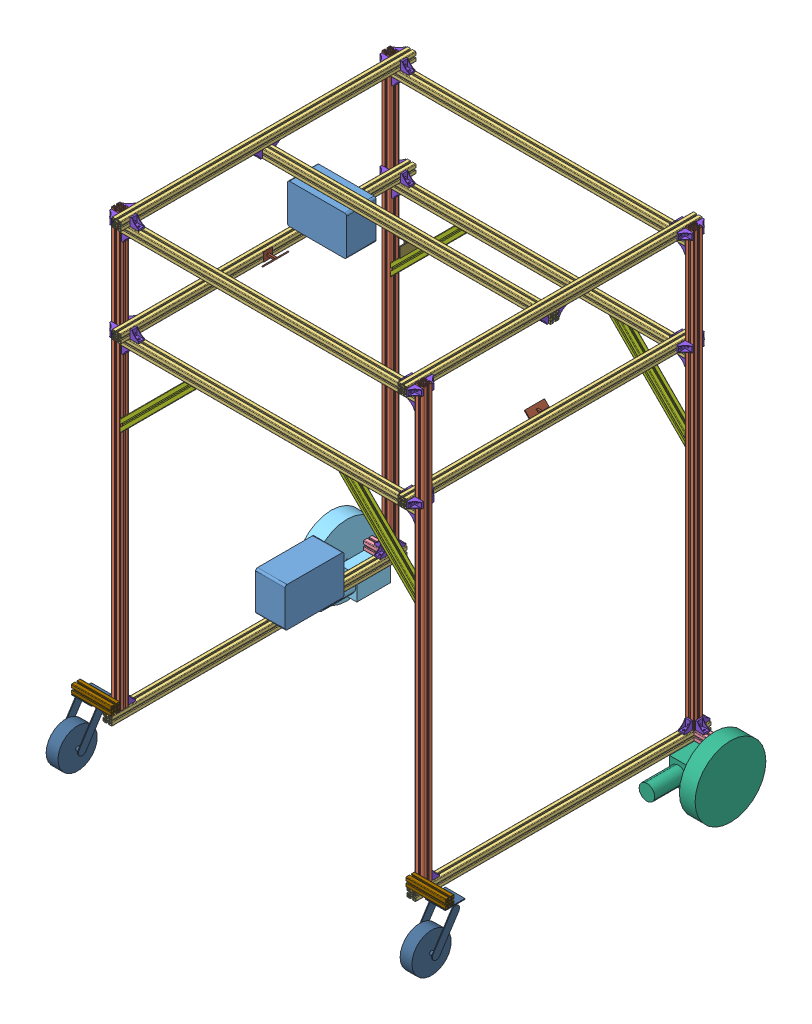
SolidWorks assembly cad, configuration Default. Lengths in mm.
Overall size (2030 2475 1715).
77 component instances, 13 part files, 154 mates.
Components (placement in the parent):
- frame-1: part_frame [Default] at origin size (1890 2245 1520) (hidden)
- box-1: part_box [Default] at (-233.0218 271.2252 -505.6193) x (0 0 -1) z (1 0 0) size (300 200 150)
- box-2: part_box [Default] at (46.9782 2181.2252 -538.1193) size (300 200 150)
- NFSL8_4545_2200-1: part_NFSL8_4545_2200 [Default] at (1374.4782 271.2252 -1128.1193) x (1 0 0) z (0 -1 0) size (45 45 2200)
- NFSL8_4545_2200-3: part_NFSL8_4545_2200 [Default] at (-170.5218 271.2252 -1128.1193) x (1 0 0) z (0 -1 0) size (45 45 2200)
- NFSL8_4545_2200-4: part_NFSL8_4545_2200 [Default] at (1374.4782 271.2252 246.8807) x (1 0 0) z (0 -1 0) size (45 45 2200)
- NFSL8_4545_2200-5: part_NFSL8_4545_2200 [Default] at (-170.5218 271.2252 246.8807) x (1 0 0) z (0 -1 0) size (45 45 2200)
- NFSL8_4545_1500-1: part_NFSL8_4545_1500 [Default] at (1374.4782 248.7252 -1190.6193) x (1 0 0) z (0 0 -1) size (45 45 1500)
- NFSL8_4545_1500-2: part_NFSL8_4545_1500 [Default] at (-170.5218 248.7252 -1190.6193) x (1 0 0) z (0 0 -1) size (45 45 1500)
- NFSL8_4545_90-1: part_NFSL8_4545_90 [Default] at (-193.0218 248.7252 -1128.1193) x (0 0 -1) z (1 0 0) size (45 45 90)
- NFSL8_4545_90-2: part_NFSL8_4545_90 [Default] at (1486.9782 248.7252 -1128.1193) x (0 0 -1) z (1 0 0) size (45 45 90)
- NFSL8_4545_1500-3: part_NFSL8_4545_1500 [Default] at (-125.5218 2448.7252 309.3807) size (45 45 1500)
- NFSL8_4545_1500-4: part_NFSL8_4545_1500 [Default] at (1329.4782 2448.7252 309.3807) size (45 45 1500)
- NFSL8_4545_1500-5: part_NFSL8_4545_1500 [Default] at (1351.9782 2403.7252 -1128.1193) x (0 0 -1) z (1 0 0) size (45 45 1500)
- NFSL8_4545_1500-8: part_NFSL8_4545_1500 [Default] at (1351.9782 2403.7252 -440.6193) x (0 0 -1) z (1 0 0) size (45 45 1500)
- NFSL8_4545_1500-9: part_NFSL8_4545_1500 [Default] at (1351.9782 2403.7252 246.8807) x (0 0 -1) z (1 0 0) size (45 45 1500)
- NFSL8_4545_1500-10: part_NFSL8_4545_1500 [Default] at (-125.5218 1953.7252 309.3807) size (45 45 1500)
- NFSL8_4545_1500-11: part_NFSL8_4545_1500 [Default] at (1329.4782 1953.7252 309.3807) size (45 45 1500)
- NFSL8_4545_1500-12: part_NFSL8_4545_1500 [Default] at (1351.9782 1908.7252 246.8807) x (0 0 -1) z (1 0 0) size (45 45 1500)
- NFSL8_4545_1500-13: part_NFSL8_4545_1500 [Default] at (1351.9782 1908.7252 -1128.1193) x (0 0 -1) z (1 0 0) size (45 45 1500)
- frontL-1: part_frontL [Default] at (-193.0218 106.2252 -1150.6193) x (-1 0 0) z (0 0 -1) size (220 360 430)
- frontR-1: part_frontR [Default] at (1396.9782 106.2252 -1150.6193) x (-1 0 0) z (0 0 -1) size (220 360 430)
- HFSL8_4545_550_LCT45_RCT45-1: part_HFSL8_4545_550_LCT45_RCT45 [Default] at (224.977 1902.1351 -1128.1193) x (0 0 -1) z (0.707107 0.707107 0) size (45 45 550)
- HFSL8_4545_550_LCT45_RCT45-2: part_HFSL8_4545_550_LCT45_RCT45 [Default] at (978.9794 1902.1351 -1128.1193) x (0 0 1) z (-0.707107 0.707107 0) size (45 45 550)
- HFSL8_4545_550_LCT45_RCT45-3: part_HFSL8_4545_550_LCT45_RCT45 [Default] at (224.977 1902.1351 246.8807) x (0 0 -1) z (0.707107 0.707107 0) size (45 45 550)
- HFSL8_4545_550_LCT45_RCT45-4: part_HFSL8_4545_550_LCT45_RCT45 [Default] at (978.9794 1902.1351 246.8807) x (0 0 1) z (-0.707107 0.707107 0) size (45 45 550)
- HBLFSN8-1: part_HBLFSN8 [Default] at (-170.5218 271.2252 -1105.6193) size (30 45 45)
- HBLFSN8-2: part_HBLFSN8 [Default] at (-193.0218 271.2252 -1128.1193) x (0 0 1) z (-1 0 0) size (30 45 45)
- HBLFSN8-3: part_HBLFSN8 [Default] at (-170.5218 268.8279 -1150.6193) x (-1 0 0) z (0 0 -1) size (30 45 45)
- HBLFSN8-4: part_HBLFSN8 [Default] at (1396.9782 271.2252 -1128.1193) x (0 0 -1) z (1 0 0) size (30 45 45)
- HBLFSN8-5: part_HBLFSN8 [Default] at (1374.4782 271.2252 -1150.6193) x (-1 0 0) z (0 0 -1) size (30 45 45)
- HBLFSN8-6: part_HBLFSN8 [Default] at (1374.4782 271.2252 -1105.6193) size (30 45 45)
- HBLFSN8-7: part_HBLFSN8 [Default] at (-103.0218 1931.2252 246.8807) x (0 0 -1) z (1 0 0) size (30 45 45)
- HBLFSN8-8: part_HBLFSN8 [Default] at (-148.0218 1886.2252 246.8807) x (0 0 1) z (1 0 0) size (30 45 45)
- HBLFSN8-9: part_HBLFSN8 [Default] at (-148.0218 1953.7252 224.3807) x (0 1 0) z (-1 0 0) size (30 45 45)
- HBLFSN8-10: part_HBLFSN8 [Default] at (1306.9782 1931.2252 246.8807) x (0 0 1) z (-1 0 0) size (30 45 45)
- HBLFSN8-11: part_HBLFSN8 [Default] at (1351.9782 1886.2252 246.8807) x (0 0 -1) z (-1 0 0) size (30 45 45)
- HBLFSN8-12: part_HBLFSN8 [Default] at (1351.9782 1953.7252 224.3807) x (0 1 0) z (0 0 -1) size (30 45 45)
- HBLFSN8-13: part_HBLFSN8 [Default] at (1329.4782 2426.2252 -418.1193) x (-1 0 0) z (0 0 1) size (30 45 45)
- HBLFSN8-14: part_HBLFSN8 [Default] at (1329.4782 2426.2252 -463.1193) x (1 0 0) z (0 0 -1) size (30 45 45)
- HBLFSN8-15: part_HBLFSN8 [Default] at (-125.5218 2426.2252 -463.1193) x (1 0 0) z (0 0 -1) size (30 45 45)
- HBLFSN8-16: part_HBLFSN8 [Default] at (-125.5218 2426.2252 -418.1193) x (-1 0 0) z (0 0 1) size (30 45 45)
- HBLFSN8-18: part_HBLFSN8 [Default] at (-170.5218 271.2252 224.3807) x (-1 0 0) z (0 0 -1) size (30 45 45)
- HBLFSN8-19: part_HBLFSN8 [Default] at (1374.4782 271.2252 224.3807) x (-1 0 0) z (0 0 -1) size (30 45 45)
- HBLFSN8-22: part_HBLFSN8 [Default] at (1306.9782 1931.2252 -1128.1193) x (0 0 1) z (-1 0 0) size (30 45 45)
- HBLFSN8-23: part_HBLFSN8 [Default] at (1351.9782 1886.2252 -1128.1193) x (0 0 -1) z (-1 0 0) size (30 45 45)
- HBLFSN8-24: part_HBLFSN8 [Default] at (1351.9782 1953.7252 -1105.6193) x (0 -1 0) z (0 0 1) size (30 45 45)
- HBLFSN8-25: part_HBLFSN8 [Default] at (-103.0218 1931.2252 -1128.1193) x (0 0 -1) z (1 0 0) size (30 45 45)
- HBLFSN8-26: part_HBLFSN8 [Default] at (-148.0218 1886.2252 -1128.1193) x (0 0 1) z (1 0 0) size (30 45 45)
- HBLFSN8-27: part_HBLFSN8 [Default] at (-148.0218 1953.7252 -1105.6193) x (0 1 0) z (0 0 1) size (30 45 45)
- HBLFSN8-28: part_HBLFSN8 [Default] at (1351.9782 1953.7252 269.3807) x (0 -1 0) z (0 0 1) size (30 45 45)
- HBLFSN8-29: part_HBLFSN8 [Default] at (1351.9782 1953.7252 -1150.6193) x (0 1 0) z (0 0 -1) size (30 45 45)
- HBLFSN8-30: part_HBLFSN8 [Default] at (-148.0218 1953.7252 -1150.6193) x (0 1 0) z (-1 0 0) size (30 45 45)
- HBLFSN8-31: part_HBLFSN8 [Default] at (-148.0218 1953.7252 269.3807) x (0 1 0) z (0 0 1) size (30 45 45)
- HBLFSN8-32: part_HBLFSN8 [Default] at (-103.0218 2426.2252 -1128.1193) x (0 0 -1) z (1 0 0) size (30 45 45)
- HBLFSN8-33: part_HBLFSN8 [Default] at (1351.9782 2381.2252 246.8807) x (0 0 -1) z (-1 0 0) size (30 45 45)
- HBLFSN8-34: part_HBLFSN8 [Default] at (1306.9782 2426.2252 246.8807) x (0 0 1) z (-1 0 0) size (30 45 45)
- HBLFSN8-35: part_HBLFSN8 [Default] at (1351.9782 2448.7252 269.3807) x (0 -1 0) z (0 0 1) size (30 45 45)
- HBLFSN8-36: part_HBLFSN8 [Default] at (1351.9782 2448.7252 224.3807) x (0 1 0) z (0 0 -1) size (30 45 45)
- HBLFSN8-37: part_HBLFSN8 [Default] at (1351.9782 2448.7252 -1105.6193) x (0 -1 0) z (0 0 1) size (30 45 45)
- HBLFSN8-38: part_HBLFSN8 [Default] at (1351.9782 2448.7252 -1150.6193) x (0 1 0) z (0 0 -1) size (30 45 45)
- HBLFSN8-39: part_HBLFSN8 [Default] at (1306.9782 2426.2252 -1128.1193) x (0 0 1) z (-1 0 0) size (30 45 45)
- HBLFSN8-40: part_HBLFSN8 [Default] at (1351.9782 2381.2252 -1128.1193) x (0 0 -1) z (-1 0 0) size (30 45 45)
- HBLFSN8-41: part_HBLFSN8 [Default] at (-148.0218 2448.7252 269.3807) x (0 1 0) z (0 0 1) size (30 45 45)
- HBLFSN8-42: part_HBLFSN8 [Default] at (-148.0218 2448.7252 224.3807) x (0 1 0) z (-1 0 0) size (30 45 45)
- HBLFSN8-43: part_HBLFSN8 [Default] at (-148.0218 2381.2252 246.8807) x (0 0 1) z (1 0 0) size (30 45 45)
- HBLFSN8-44: part_HBLFSN8 [Default] at (-103.0218 2426.2252 246.8807) x (0 0 -1) z (1 0 0) size (30 45 45)
- HBLFSN8-45: part_HBLFSN8 [Default] at (-148.0218 2381.2252 -1128.1193) x (0 0 1) z (1 0 0) size (30 45 45)
- HBLFSN8-46: part_HBLFSN8 [Default] at (-148.0218 2448.7252 -1105.6193) x (0 1 0) z (0 0 1) size (30 45 45)
- HBLFSN8-47: part_HBLFSN8 [Default] at (-148.0218 2448.7252 -1150.6193) x (0 1 0) z (-1 0 0) size (30 45 45)
- NFSL8_4545_200-3: part_NFSL8_4545_200 [Default] at (-348.0218 293.7252 291.8807) x (0 0 1) z (-1 0 0) size (45 45 200)
- NFSL8_4545_200-4: part_NFSL8_4545_200 [Default] at (1351.9782 293.7252 291.8807) x (0 0 1) z (-1 0 0) size (45 45 200)
- rearwheel-5: part_rearwheel [Default] at (1501.9782 97.2252 364.3807) size (108 274 250)
- rearwheel-6: part_rearwheel [Default] at (-298.0218 97.2252 364.3807) size (108 274 250)
- camerabracket_side-1: part_camerabracket_side [Default] at (-103.0218 1976.2252 -416.1503) x (0 -1 0) z (0 0 1) size (45 57.2 100)
- camerabracket_side-2: part_camerabracket_side [Default] at (1306.9782 1976.2252 -461.1503) x (0 -1 0) z (0 0 -1) size (45 57.2 100)
- camerabracket_top-1: part_camerabracket_top [Default] at (574.846 2381.2252 -463.1193) x (1 0 0) z (0 0 -1) size (45 61.03 100)
Mates (geometry in assembly coordinates):
- Coincident9: coincident aligned: plane of NFSL8_4545_2200-1 through (1396.9782 2471.2252 -1123.1193) normal (1 0 0); plane of NFSL8_4545_1500-1 through (1396.9782 268.2252 309.3807) normal (1 0 0)
- Coincident10: coincident anti-aligned: plane of NFSL8_4545_2200-4 through (1354.9782 271.2252 227.3807) normal (0 -1 0); plane of NFSL8_4545_1500-1 through (1379.4782 271.2252 309.3807) normal (0 1 0)
- Coincident29: coincident aligned: line of NFSL8_4545_2200-3 through (-193.0218 271.2252 -1133.1193) axis (0 0 -1); line of NFSL8_4545_200-1 through (-193.0218 271.2252 241.8807) axis (0 0 -1)
- Perpendicular17: perpendicular: plane of NFSL8_4545_2200-3 through (-193.0218 2471.2252 -1133.1193) normal (-1 0 0); plane of NFSL8_4545_200-1 through (-193.0218 271.2252 241.8807) normal (0 1 0)
- Coincident27: coincident aligned: plane of NFSL8_4545_2200-5 through (-151.0218 2471.2252 269.3807) normal (0 0 1); plane of NFSL8_4545_200-1 through (-193.0218 253.7252 269.3807) normal (0 0 1)
- Coincident30: coincident anti-aligned: line of NFSL8_4545_2200-5 through (-193.0218 271.2252 241.8807) axis (0 0 -1); line of NFSL8_4545_90-1 through (-193.0218 271.2252 -1147.6193) axis (0 0 1)
- Coincident33: coincident aligned: plane of NFSL8_4545_90-1 through (-283.0218 253.7252 -1150.6193) normal (0 0 -1); plane of NFSL8_4545_2200-3 through (-190.0218 2471.2252 -1150.6193) normal (0 0 -1)
- Coincident35: coincident anti-aligned: plane of NFSL8_4545_2200-5 through (-148.0218 2471.2252 251.8807) normal (1 0 0); plane of NFSL8_4545_1500-3 through (-148.0218 2468.2252 -1190.6193) normal (-1 0 0)
- Coincident37: coincident aligned: plane of NFSL8_4545_1500-2 through (-190.0218 268.2252 309.3807) normal (0 0 1); plane of NFSL8_4545_1500-3 through (-145.0218 2429.2252 309.3807) normal (0 0 1)
- Coincident40: coincident anti-aligned: plane of NFSL8_4545_2200-3 through (-148.0218 2471.2252 -1123.1193) normal (1 0 0); plane of NFSL8_4545_1500-5 through (-148.0218 2384.2252 -1108.6193) normal (-1 0 0)
- Coincident43: coincident aligned: plane of NFSL8_4545_2200-3 through (-190.0218 2471.2252 -1147.6193) normal (0 1 0); plane of NFSL8_4545_1500-3 through (-130.5218 2471.2252 -1190.6193) normal (0 1 0)
- Coincident49: coincident anti-aligned: plane of NFSL8_4545_1500-3 through (-120.5218 2426.2252 -1190.6193) normal (0 -1 0); plane of NFSL8_4545_1500-5 through (-148.0218 2426.2252 -1123.1193) normal (0 1 0)
- Coincident55: coincident aligned: plane of NFSL8_4545_2200-3 through (-151.0218 2471.2252 -1105.6193) normal (0 0 1); plane of NFSL8_4545_1500-5 through (-148.0218 2423.2252 -1105.6193) normal (0 0 1)
- Coincident58: coincident: plane of NFSL8_4545_2200-5 through (-148.0218 2471.2252 227.3807) normal (1 0 0); line of NFSL8_4545_1500-12 through (-148.0218 1886.2252 241.8807) axis (0 0 -1)
- Coincident59: coincident anti-aligned: plane of NFSL8_4545_1500-12 through (-148.0218 1931.2252 251.8807) normal (0 1 0); plane of NFSL8_4545_1500-10 through (-120.5218 1931.2252 -1190.6193) normal (0 -1 0)
- Coincident60: coincident aligned: plane of NFSL8_4545_2200-5 through (-165.5218 2471.2252 224.3807) normal (0 0 -1); plane of NFSL8_4545_1500-12 through (-148.0218 1913.7252 224.3807) normal (0 0 -1)
- Distance1: distance = 40 mm: plane of NFSL8_4545_2200-4 through (1369.4782 2471.2252 269.3807) normal (0 0 1); line of NFSL8_4545_1500-1 through (1354.9782 271.2252 309.3807) axis (1 0 0)
- Parallel15: parallel aligned: plane of box-1 through (-233.0218 271.2252 -505.6193) normal (-1 0 0); plane of NFSL8_4545_1500-2 through (-193.0218 253.7252 309.3807) normal (-1 0 0)
- Coincident63: coincident anti-aligned: plane of box-1 through (-83.0218 271.2252 -505.6193) normal (0 -1 0); plane of NFSL8_4545_1500-2 through (-190.0218 271.2252 309.3807) normal (0 1 0)
- Distance2: distance = 300 mm anti-aligned: plane of NFSL8_4545_2200-3 through (-175.5218 2471.2252 -1105.6193) normal (0 0 1); plane of box-1 through (-83.0218 271.2252 -805.6193) normal (0 0 -1)
- Distance3: distance = 40 mm: plane of NFSL8_4545_1500-2 through (-193.0218 253.7252 309.3807) normal (-1 0 0); line of box-1 through (-233.0218 271.2252 -515.6193) axis (0 0 -1)
- Coincident66: coincident anti-aligned: plane of box-2 through (46.9782 2381.2252 -388.1193) normal (0 1 0); plane of NFSL8_4545_1500-8 through (-148.0218 2381.2252 -421.1193) normal (0 -1 0)
- Parallel16: parallel aligned: plane of box-2 through (346.9782 2181.2252 -388.1193) normal (1 0 0); plane of NFSL8_4545_1500-3 through (-103.0218 2453.7252 -1190.6193) normal (1 0 0)
- Distance4: distance = 150 mm anti-aligned: plane of NFSL8_4545_1500-3 through (-103.0218 2429.2252 -1190.6193) normal (1 0 0); plane of box-2 through (46.9782 2181.2252 -388.1193) normal (-1 0 0)
- Distance5: distance = 30 mm aligned: plane of NFSL8_4545_1500-8 through (-148.0218 2398.7252 -418.1193) normal (0 0 1); plane of box-2 through (46.9782 2181.2252 -388.1193) normal (0 0 1)
- Coincident70: coincident anti-aligned: plane of NFSL8_4545_1500-2 through (-193.0218 229.2252 309.3807) normal (-1 0 0); plane of frontL-1 through (-193.0218 106.2252 -1150.6193) normal (1 0 0)
- Coincident71: coincident aligned: plane of NFSL8_4545_90-1 through (-283.0218 229.2252 -1150.6193) normal (0 0 -1); plane of frontL-1 through (-283.0218 106.2252 -1150.6193) normal (0 0 -1)
- Coincident72: coincident aligned: plane of NFSL8_4545_90-2 through (1396.9782 229.2252 -1150.6193) normal (0 0 -1); plane of frontR-1 through (1486.9782 106.2252 -1150.6193) normal (0 0 -1)
- Coincident73: coincident: plane of NFSL8_4545_1500-1 through (1369.4782 226.2252 309.3807) normal (0 -1 0); line of frontR-1 through (1396.9782 226.2252 -980.6193) axis (0 0 -1)
- Coincident74: coincident anti-aligned: plane of NFSL8_4545_1500-1 through (1396.9782 243.7252 309.3807) normal (1 0 0); plane of frontR-1 through (1396.9782 106.2252 -1150.6193) normal (-1 0 0)
- Coincident75: coincident aligned: plane of NFSL8_4545_200-1 through (-393.0218 268.2252 266.3807) normal (-1 0 0); plane of plate-1 through (-393.0218 226.2252 258.3807) normal (-1 0 0)
- Coincident76: coincident aligned: plane of NFSL8_4545_200-1 through (-193.0218 236.0403 258.3807) normal (0 0 1); plane of plate-1 through (-393.0218 226.2252 258.3807) normal (0 0 1)
- Coincident80: coincident anti-aligned: plane of NFSL8_4545_200-1 through (-193.0218 226.2252 251.8807) normal (0 -1 0); plane of plate-1 through (-393.0218 226.2252 258.3807) normal (0 1 0)
- Coincident81: coincident anti-aligned: plane of plate-2 through (1596.9782 226.2252 258.3807) normal (1 0 0); plane of rearwheel-1 through (1596.9782 92.9526 256.107) normal (-1 0 0)
- Tangent1: tangent aligned: plane of plate-2 through (1496.9782 226.2252 258.3807) normal (0 1 0); cylinder of rearwheel-1 through (1600.9782 205.7157 215.0646) axis (-1 0 0) radius 20.5095
- Angle2: planar angle = 1.919862 rad aligned: line of rearwheel-1 through (1600.9782 198.701 195.792) axis (0 -0.939693 0.34202); line of plate-2 through (1596.9782 222.2252 258.3807) axis (0 0 -1)
- Coincident86: coincident anti-aligned: plane of NFSL8_4545_2200-5 through (-148.0218 2471.2252 251.8807) normal (1 0 0); plane of NFSL8_4545_450_LCT45_RCT45-1 through (-148.0218 1658.0271 269.3807) normal (-1 0 0)
- Coincident87: coincident anti-aligned: plane of NFSL8_4545_1500-12 through (-148.0218 1886.2252 266.3807) normal (0 -1 0); plane of NFSL8_4545_450_LCT45_RCT45-1 through (106.5366 1976.2252 269.3807) normal (0 1 0)
- Coincident88: coincident aligned: plane of NFSL8_4545_2200-5 through (-175.5218 2471.2252 269.3807) normal (0 0 1); plane of NFSL8_4545_450_LCT45_RCT45-1 through (150.7308 1995.6706 269.3807) normal (0 0 1)
- Coincident89: coincident anti-aligned: plane of NFSL8_4545_2200-4 through (1351.9782 2471.2252 266.3807) normal (-1 0 0); plane of NFSL8_4545_450_LCT45_RCT45-2 through (1351.9782 1568.0271 224.3807) normal (1 0 0)
- Coincident90: coincident anti-aligned: plane of NFSL8_4545_1500-12 through (-148.0218 1886.2252 266.3807) normal (0 -1 0); plane of NFSL8_4545_450_LCT45_RCT45-2 through (1097.4198 1886.2252 224.3807) normal (0 1 0)
- Coincident91: coincident aligned: plane of NFSL8_4545_1500-12 through (-148.0218 1903.7252 269.3807) normal (0 0 1); plane of NFSL8_4545_450_LCT45_RCT45-2 through (1063.4786 1915.9237 269.3807) normal (0 0 1)
- Coincident96: coincident aligned: plane of NFSL8_4545_2200-3 through (-165.5218 2471.2252 -1150.6193) normal (0 0 -1); plane of HFSL8_4545_550_LCT45_RCT45-1 through (-150.1431 1499.4378 -1150.6193) normal (0 0 -1)
- Coincident98: coincident aligned: plane of NFSL8_4545_1500-13 through (-148.0218 1903.7252 -1105.6193) normal (0 0 1); plane of HFSL8_4545_550_LCT45_RCT45-1 through (-177.7203 1527.0149 -1105.6193) normal (0 0 1)
- Coincident99: coincident anti-aligned: plane of NFSL8_4545_2200-3 through (-148.0218 2471.2252 -1123.1193) normal (1 0 0); plane of HFSL8_4545_550_LCT45_RCT45-1 through (-148.0218 1560.9561 -1150.6193) normal (-1 0 0)
- Coincident100: coincident anti-aligned: plane of NFSL8_4545_1500-13 through (-148.0218 1886.2252 -1133.1193) normal (0 -1 0); plane of HFSL8_4545_550_LCT45_RCT45-1 through (240.8869 1886.2252 -1150.6193) normal (0 1 0)
- Coincident102: coincident aligned: plane of NFSL8_4545_2200-1 through (1354.9782 2471.2252 -1150.6193) normal (0 0 -1); plane of HFSL8_4545_550_LCT45_RCT45-2 through (1381.6767 1527.0149 -1150.6193) normal (0 0 -1)
- Coincident103: coincident aligned: plane of NFSL8_4545_2200-1 through (1369.4782 2471.2252 -1105.6193) normal (0 0 1); plane of HFSL8_4545_550_LCT45_RCT45-2 through (1371.4236 1516.7619 -1105.6193) normal (0 0 1)
- Coincident104: coincident anti-aligned: plane of NFSL8_4545_2200-1 through (1351.9782 2471.2252 -1133.1193) normal (-1 0 0); plane of HFSL8_4545_550_LCT45_RCT45-2 through (1351.9782 1560.9561 -1105.6193) normal (1 0 0)
- Coincident105: coincident anti-aligned: plane of NFSL8_4545_1500-13 through (-148.0218 1886.2252 -1133.1193) normal (0 -1 0); plane of HFSL8_4545_550_LCT45_RCT45-2 through (963.0695 1886.2252 -1105.6193) normal (0 1 0)
- Coincident106: coincident anti-aligned: plane of NFSL8_4545_2200-3 through (-151.0218 2471.2252 -1105.6193) normal (0 0 1); plane of HBLFSN8-1 through (-170.5218 271.2252 -1105.6193) normal (0 0 -1)
- Coincident107: coincident anti-aligned: plane of NFSL8_4545_1500-2 through (-165.5218 271.2252 309.3807) normal (0 1 0); plane of HBLFSN8-1 through (-170.5218 271.2252 -1105.6193) normal (0 -1 0)
- Coincident108: coincident anti-aligned: plane of NFSL8_4545_1500-2 through (-165.5218 265.7252 309.3807) normal (-1 0 0); plane of HBLFSN8-1 through (-165.5218 269.2252 -1067.9193) normal (1 0 0)
- Coincident109: coincident anti-aligned: plane of NFSL8_4545_2200-3 through (-193.0218 2471.2252 -1133.1193) normal (-1 0 0); plane of HBLFSN8-2 through (-193.0218 271.2252 -1128.1193) normal (1 0 0)
- Coincident110: coincident anti-aligned: plane of NFSL8_4545_90-1 through (-283.0218 271.2252 -1147.6193) normal (0 1 0); plane of HBLFSN8-2 through (-193.0218 271.2252 -1128.1193) normal (0 -1 0)
- Coincident111: coincident anti-aligned: plane of NFSL8_4545_90-1 through (-283.0218 271.2252 -1133.1193) normal (0 0 1); plane of HBLFSN8-2 through (-198.3218 269.2252 -1133.1193) normal (0 0 -1)
- Coincident112: coincident anti-aligned: plane of NFSL8_4545_1500-2 through (-165.5218 265.7252 309.3807) normal (-1 0 0); plane of HBLFSN8-3 through (-165.5218 266.8279 -1155.9193) normal (1 0 0)
- Coincident113: coincident anti-aligned: plane of NFSL8_4545_2200-3 through (-165.5218 2471.2252 -1150.6193) normal (0 0 -1); plane of HBLFSN8-3 through (-170.5218 268.8279 -1150.6193) normal (0 0 1)
- Coincident114: coincident anti-aligned: plane of NFSL8_4545_2200-1 through (1396.9782 2471.2252 -1123.1193) normal (1 0 0); plane of HBLFSN8-4 through (1396.9782 271.2252 -1128.1193) normal (-1 0 0)
- Coincident115: coincident anti-aligned: plane of NFSL8_4545_90-2 through (1396.9782 271.2252 -1123.1193) normal (0 1 0); plane of HBLFSN8-4 through (1396.9782 271.2252 -1128.1193) normal (0 -1 0)
- Coincident116: coincident anti-aligned: plane of NFSL8_4545_90-2 through (1396.9782 271.2252 -1133.1193) normal (0 0 1); plane of HBLFSN8-4 through (1409.6782 269.2252 -1133.1193) normal (0 0 -1)
- Coincident117: coincident anti-aligned: plane of NFSL8_4545_2200-1 through (1354.9782 2471.2252 -1150.6193) normal (0 0 -1); plane of HBLFSN8-5 through (1374.4782 271.2252 -1150.6193) normal (0 0 1)
- Coincident118: coincident anti-aligned: plane of NFSL8_4545_1500-1 through (1379.4782 271.2252 309.3807) normal (0 1 0); plane of HBLFSN8-5 through (1374.4782 271.2252 -1150.6193) normal (0 -1 0)
- Coincident119: coincident anti-aligned: plane of NFSL8_4545_1500-1 through (1379.4782 265.7252 309.3807) normal (-1 0 0); plane of HBLFSN8-5 through (1379.4782 269.2252 -1155.9193) normal (1 0 0)
- Coincident120: coincident anti-aligned: plane of NFSL8_4545_2200-1 through (1369.4782 2471.2252 -1105.6193) normal (0 0 1); plane of HBLFSN8-6 through (1374.4782 271.2252 -1105.6193) normal (0 0 -1)
- Coincident121: coincident anti-aligned: plane of NFSL8_4545_1500-1 through (1379.4782 271.2252 309.3807) normal (0 1 0); plane of HBLFSN8-6 through (1374.4782 271.2252 -1105.6193) normal (0 -1 0)
- Coincident122: coincident anti-aligned: plane of NFSL8_4545_1500-1 through (1369.4782 271.2252 309.3807) normal (1 0 0); plane of HBLFSN8-6 through (1369.4782 269.2252 -1100.3193) normal (-1 0 0)
- Coincident123: coincident anti-aligned: plane of NFSL8_4545_1500-10 through (-103.0218 1958.7252 -1190.6193) normal (1 0 0); plane of HBLFSN8-7 through (-103.0218 1931.2252 246.8807) normal (-1 0 0)
- Coincident124: coincident anti-aligned: plane of NFSL8_4545_1500-12 through (-148.0218 1931.2252 251.8807) normal (0 1 0); plane of HBLFSN8-7 through (-103.0218 1931.2252 246.8807) normal (0 -1 0)
- Coincident125: coincident anti-aligned: plane of NFSL8_4545_1500-12 through (-148.0218 1931.2252 241.8807) normal (0 0 1); plane of HBLFSN8-7 through (-90.3218 1929.2252 241.8807) normal (0 0 -1)
- Coincident126: coincident anti-aligned: plane of NFSL8_4545_2200-5 through (-148.0218 2471.2252 251.8807) normal (1 0 0); plane of HBLFSN8-8 through (-148.0218 1886.2252 246.8807) normal (-1 0 0)
- Coincident127: coincident anti-aligned: plane of NFSL8_4545_1500-12 through (-148.0218 1886.2252 266.3807) normal (0 -1 0); plane of HBLFSN8-8 through (-148.0218 1886.2252 246.8807) normal (0 1 0)
- Coincident128: coincident anti-aligned: plane of NFSL8_4545_1500-12 through (-148.0218 1886.2252 251.8807) normal (0 0 -1); plane of HBLFSN8-8 through (-135.3218 1888.2252 251.8807) normal (0 0 1)
- Coincident129: coincident anti-aligned: plane of NFSL8_4545_1500-10 through (-148.0218 1948.7252 -1190.6193) normal (-1 0 0); plane of HBLFSN8-9 through (-148.0218 1953.7252 224.3807) normal (1 0 0)
- Coincident130: coincident anti-aligned: plane of NFSL8_4545_2200-5 through (-190.0218 2471.2252 224.3807) normal (0 0 -1); plane of HBLFSN8-9 through (-148.0218 1953.7252 224.3807) normal (0 0 1)
- Coincident131: coincident anti-aligned: plane of NFSL8_4545_1500-10 through (-148.0218 1958.7252 -1190.6193) normal (0 -1 0); plane of HBLFSN8-9 through (-146.0218 1958.7252 208.3807) normal (0 1 0)
- Coincident132: coincident anti-aligned: plane of NFSL8_4545_1500-11 through (1306.9782 1948.7252 -1190.6193) normal (-1 0 0); plane of HBLFSN8-10 through (1306.9782 1931.2252 246.8807) normal (1 0 0)
- Coincident133: coincident anti-aligned: plane of NFSL8_4545_1500-12 through (-148.0218 1931.2252 227.3807) normal (0 1 0); plane of HBLFSN8-10 through (1306.9782 1931.2252 246.8807) normal (0 -1 0)
- Coincident134: coincident anti-aligned: plane of NFSL8_4545_1500-12 through (-148.0218 1931.2252 241.8807) normal (0 0 1); plane of HBLFSN8-10 through (1301.6782 1929.2252 241.8807) normal (0 0 -1)
- Coincident135: coincident anti-aligned: plane of NFSL8_4545_2200-4 through (1351.9782 2471.2252 241.8807) normal (-1 0 0); plane of HBLFSN8-11 through (1351.9782 1886.2252 246.8807) normal (1 0 0)
- Coincident136: coincident anti-aligned: plane of NFSL8_4545_1500-12 through (-148.0218 1886.2252 241.8807) normal (0 -1 0); plane of HBLFSN8-11 through (1351.9782 1886.2252 246.8807) normal (0 1 0)
- Coincident137: coincident anti-aligned: plane of NFSL8_4545_1500-12 through (-148.0218 1891.7252 241.8807) normal (0 0 1); plane of HBLFSN8-11 through (1339.2782 1888.2252 241.8807) normal (0 0 -1)
- Coincident138: coincident anti-aligned: plane of NFSL8_4545_2200-4 through (1354.9782 2471.2252 224.3807) normal (0 0 -1); plane of HBLFSN8-12 through (1351.9782 1953.7252 224.3807) normal (0 0 1)
- Coincident139: coincident anti-aligned: plane of NFSL8_4545_1500-11 through (1351.9782 1958.7252 -1190.6193) normal (1 0 0); plane of HBLFSN8-12 through (1351.9782 1953.7252 224.3807) normal (-1 0 0)
- Coincident140: coincident anti-aligned: plane of NFSL8_4545_1500-11 through (1346.4782 1958.7252 -1190.6193) normal (0 -1 0); plane of HBLFSN8-12 through (1349.9782 1958.7252 211.6807) normal (0 1 0)
- Coincident141: coincident anti-aligned: plane of NFSL8_4545_1500-8 through (-148.0218 2423.2252 -418.1193) normal (0 0 1); plane of HBLFSN8-13 through (1329.4782 2426.2252 -418.1193) normal (0 0 -1)
- Coincident142: coincident anti-aligned: plane of NFSL8_4545_1500-4 through (1334.4782 2426.2252 -1190.6193) normal (0 -1 0); plane of HBLFSN8-13 through (1329.4782 2426.2252 -418.1193) normal (0 1 0)
- Coincident143: coincident anti-aligned: plane of NFSL8_4545_1500-4 through (1334.4782 2431.7252 -1190.6193) normal (-1 0 0); plane of HBLFSN8-13 through (1334.4782 2428.2252 -412.8193) normal (1 0 0)
- Coincident144: coincident anti-aligned: plane of NFSL8_4545_1500-8 through (-148.0218 2408.7252 -463.1193) normal (0 0 -1); plane of HBLFSN8-14 through (1329.4782 2426.2252 -463.1193) normal (0 0 1)
- Coincident145: coincident anti-aligned: plane of NFSL8_4545_1500-4 through (1334.4782 2426.2252 -1190.6193) normal (0 -1 0); plane of HBLFSN8-14 through (1329.4782 2426.2252 -463.1193) normal (0 1 0)
- Coincident146: coincident anti-aligned: plane of NFSL8_4545_1500-4 through (1334.4782 2431.7252 -1190.6193) normal (-1 0 0); plane of HBLFSN8-14 through (1334.4782 2428.2252 -475.8193) normal (1 0 0)
- Coincident147: coincident anti-aligned: plane of NFSL8_4545_2200-5 through (-175.5218 2471.2252 269.3807) normal (0 0 1); plane of HBLFSN8-17 through (-170.5218 271.2252 269.3807) normal (0 0 -1)
- Coincident148: coincident anti-aligned: plane of NFSL8_4545_1500-2 through (-165.5218 271.2252 309.3807) normal (0 1 0); plane of HBLFSN8-17 through (-170.5218 271.2252 269.3807) normal (0 -1 0)
- Coincident149: coincident anti-aligned: plane of NFSL8_4545_2200-5 through (-165.5218 2471.2252 269.3807) normal (-1 0 0); plane of HBLFSN8-17 through (-165.5218 291.7252 267.3807) normal (1 0 0)
- Coincident151: coincident anti-aligned: plane of NFSL8_4545_2200-5 through (-165.5218 2471.2252 224.3807) normal (0 0 -1); plane of HBLFSN8-18 through (-170.5218 271.2252 224.3807) normal (0 0 1)
- Coincident152: coincident anti-aligned: plane of NFSL8_4545_1500-2 through (-165.5218 271.2252 309.3807) normal (0 1 0); plane of HBLFSN8-18 through (-170.5218 271.2252 224.3807) normal (0 -1 0)
- Coincident153: coincident anti-aligned: plane of NFSL8_4545_1500-2 through (-175.5218 271.2252 309.3807) normal (1 0 0); plane of HBLFSN8-18 through (-175.5218 269.2252 211.6807) normal (-1 0 0)
- Coincident154: coincident anti-aligned: plane of NFSL8_4545_2200-4 through (1396.9782 2471.2252 251.8807) normal (1 0 0); plane of HBLFSN8-21 through (1396.9782 271.2252 246.8807) normal (-1 0 0)
- Coincident157: coincident anti-aligned: plane of NFSL8_4545_1500-11 through (1306.9782 1973.2252 -1190.6193) normal (-1 0 0); plane of HBLFSN8-22 through (1306.9782 1931.2252 -1128.1193) normal (1 0 0)
- Coincident158: coincident anti-aligned: plane of NFSL8_4545_1500-13 through (-148.0218 1931.2252 -1123.1193) normal (0 1 0); plane of HBLFSN8-22 through (1306.9782 1931.2252 -1128.1193) normal (0 -1 0)
- Coincident159: coincident anti-aligned: plane of NFSL8_4545_1500-13 through (-148.0218 1925.7252 -1123.1193) normal (0 0 -1); plane of HBLFSN8-22 through (1294.2782 1929.2252 -1123.1193) normal (0 0 1)
- Coincident160: coincident anti-aligned: plane of NFSL8_4545_2200-1 through (1351.9782 2471.2252 -1108.6193) normal (-1 0 0); plane of HBLFSN8-23 through (1351.9782 1886.2252 -1128.1193) normal (1 0 0)
- Coincident161: coincident anti-aligned: plane of NFSL8_4545_1500-13 through (-148.0218 1886.2252 -1133.1193) normal (0 -1 0); plane of HBLFSN8-23 through (1351.9782 1886.2252 -1128.1193) normal (0 1 0)
- Coincident162: coincident anti-aligned: plane of NFSL8_4545_1500-13 through (-148.0218 1891.7252 -1133.1193) normal (0 0 1); plane of HBLFSN8-23 through (1339.2782 1888.2252 -1133.1193) normal (0 0 -1)
- Coincident163: coincident anti-aligned: plane of NFSL8_4545_2200-1 through (1393.9782 2471.2252 -1105.6193) normal (0 0 1); plane of HBLFSN8-24 through (1351.9782 1953.7252 -1105.6193) normal (0 0 -1)
- Coincident164: coincident anti-aligned: plane of NFSL8_4545_1500-11 through (1351.9782 1958.7252 -1190.6193) normal (1 0 0); plane of HBLFSN8-24 through (1351.9782 1953.7252 -1105.6193) normal (-1 0 0)
- Coincident165: coincident anti-aligned: plane of NFSL8_4545_1500-11 through (1346.4782 1958.7252 -1190.6193) normal (0 -1 0); plane of HBLFSN8-24 through (1349.9782 1958.7252 -1100.3193) normal (0 1 0)
- Coincident166: coincident anti-aligned: plane of NFSL8_4545_1500-10 through (-103.0218 1958.7252 -1190.6193) normal (1 0 0); plane of HBLFSN8-25 through (-103.0218 1931.2252 -1128.1193) normal (-1 0 0)
- Coincident167: coincident anti-aligned: plane of NFSL8_4545_1500-13 through (-148.0218 1931.2252 -1123.1193) normal (0 1 0); plane of HBLFSN8-25 through (-103.0218 1931.2252 -1128.1193) normal (0 -1 0)
- Coincident168: coincident anti-aligned: plane of NFSL8_4545_1500-13 through (-148.0218 1925.7252 -1123.1193) normal (0 0 -1); plane of HBLFSN8-25 through (-97.7218 1929.2252 -1123.1193) normal (0 0 1)
- Coincident169: coincident anti-aligned: plane of NFSL8_4545_2200-3 through (-148.0218 2471.2252 -1123.1193) normal (1 0 0); plane of HBLFSN8-26 through (-148.0218 1886.2252 -1128.1193) normal (-1 0 0)
- Coincident170: coincident anti-aligned: plane of NFSL8_4545_1500-13 through (-148.0218 1886.2252 -1108.6193) normal (0 -1 0); plane of HBLFSN8-26 through (-148.0218 1886.2252 -1128.1193) normal (0 1 0)
- Coincident171: coincident anti-aligned: plane of NFSL8_4545_1500-13 through (-148.0218 1886.2252 -1123.1193) normal (0 0 -1); plane of HBLFSN8-26 through (-135.3218 1888.2252 -1123.1193) normal (0 0 1)
- Coincident172: coincident anti-aligned: plane of NFSL8_4545_2200-3 through (-151.0218 2471.2252 -1105.6193) normal (0 0 1); plane of HBLFSN8-27 through (-148.0218 1953.7252 -1105.6193) normal (0 0 -1)
- Coincident173: coincident anti-aligned: plane of NFSL8_4545_1500-10 through (-148.0218 1973.2252 -1190.6193) normal (-1 0 0); plane of HBLFSN8-27 through (-148.0218 1953.7252 -1105.6193) normal (1 0 0)
- Coincident174: coincident anti-aligned: plane of NFSL8_4545_1500-10 through (-142.5218 1948.7252 -1190.6193) normal (0 1 0); plane of HBLFSN8-27 through (-146.0218 1948.7252 -1100.3193) normal (0 -1 0)
- Coincident175: coincident anti-aligned: plane of NFSL8_4545_2200-4 through (1369.4782 2471.2252 269.3807) normal (0 0 1); plane of HBLFSN8-28 through (1351.9782 1953.7252 269.3807) normal (0 0 -1)
- Coincident176: coincident anti-aligned: plane of NFSL8_4545_1500-11 through (1351.9782 1958.7252 -1190.6193) normal (1 0 0); plane of HBLFSN8-28 through (1351.9782 1953.7252 269.3807) normal (-1 0 0)
- Coincident178: coincident anti-aligned: plane of NFSL8_4545_1500-11 through (1351.9782 1948.7252 -1190.6193) normal (0 1 0); plane of HBLFSN8-28 through (1349.9782 1948.7252 282.0807) normal (0 -1 0)
- Coincident179: coincident anti-aligned: plane of NFSL8_4545_2200-1 through (1379.4782 2471.2252 -1150.6193) normal (0 0 -1); plane of HBLFSN8-29 through (1351.9782 1953.7252 -1150.6193) normal (0 0 1)
- Coincident180: coincident anti-aligned: plane of NFSL8_4545_1500-11 through (1351.9782 1958.7252 -1190.6193) normal (1 0 0); plane of HBLFSN8-29 through (1351.9782 1953.7252 -1150.6193) normal (-1 0 0)
- Coincident181: coincident anti-aligned: plane of NFSL8_4545_1500-11 through (1346.4782 1958.7252 -1190.6193) normal (0 -1 0); plane of HBLFSN8-29 through (1349.9782 1958.7252 -1163.3193) normal (0 1 0)
- Coincident182: coincident anti-aligned: plane of NFSL8_4545_1500-10 through (-148.0218 1973.2252 -1190.6193) normal (-1 0 0); plane of HBLFSN8-30 through (-148.0218 1953.7252 -1150.6193) normal (1 0 0)
- Coincident183: coincident anti-aligned: plane of NFSL8_4545_2200-3 through (-165.5218 2471.2252 -1150.6193) normal (0 0 -1); plane of HBLFSN8-30 through (-148.0218 1953.7252 -1150.6193) normal (0 0 1)
- Coincident184: coincident anti-aligned: plane of NFSL8_4545_1500-10 through (-142.5218 1948.7252 -1190.6193) normal (0 1 0); plane of HBLFSN8-30 through (-146.0218 1948.7252 -1174.6193) normal (0 -1 0)
- Coincident185: coincident anti-aligned: plane of NFSL8_4545_1500-10 through (-148.0218 1973.2252 -1190.6193) normal (-1 0 0); plane of HBLFSN8-31 through (-148.0218 1953.7252 269.3807) normal (1 0 0)
- Coincident186: coincident anti-aligned: plane of NFSL8_4545_2200-5 through (-175.5218 2471.2252 269.3807) normal (0 0 1); plane of HBLFSN8-31 through (-148.0218 1953.7252 269.3807) normal (0 0 -1)
- Coincident187: coincident anti-aligned: plane of NFSL8_4545_1500-10 through (-148.0218 1958.7252 -1190.6193) normal (0 -1 0); plane of HBLFSN8-31 through (-146.0218 1958.7252 282.0807) normal (0 1 0)
- Coincident188: coincident anti-aligned: plane of NFSL8_4545_2200-5 through (-151.0218 2471.2252 269.3807) normal (0 0 1); plane of NFSL8_4545_200-3 through (-148.0218 313.2252 269.3807) normal (0 0 -1)
- Coincident189: coincident anti-aligned: plane of NFSL8_4545_1500-2 through (-165.5218 271.2252 309.3807) normal (0 1 0); plane of NFSL8_4545_200-3 through (-148.0218 271.2252 296.8807) normal (0 -1 0)
- Coincident190: coincident aligned: plane of NFSL8_4545_1500-2 through (-148.0218 268.2252 309.3807) normal (1 0 0); plane of NFSL8_4545_200-3 through (-148.0218 274.2252 272.3807) normal (1 0 0)
- Coincident191: coincident anti-aligned: plane of NFSL8_4545_2200-4 through (1369.4782 2471.2252 269.3807) normal (0 0 1); plane of NFSL8_4545_200-4 through (1551.9782 313.2252 269.3807) normal (0 0 -1)
- Coincident192: coincident anti-aligned: plane of NFSL8_4545_1500-1 through (1379.4782 271.2252 309.3807) normal (0 1 0); plane of NFSL8_4545_200-4 through (1551.9782 271.2252 272.3807) normal (0 -1 0)
- Coincident193: coincident aligned: plane of NFSL8_4545_1500-1 through (1351.9782 229.2252 309.3807) normal (-1 0 0); plane of NFSL8_4545_200-4 through (1351.9782 274.2252 272.3807) normal (-1 0 0)
- Coincident194: coincident aligned: plane of NFSL8_4545_200-4 through (1551.9782 298.7252 314.3807) normal (0 0 1); plane of plate-3 through (1451.9782 271.2252 314.3807) normal (0 0 1)
- Coincident195: coincident aligned: plane of NFSL8_4545_200-4 through (1551.9782 274.2252 272.3807) normal (1 0 0); plane of plate-3 through (1551.9782 271.2252 314.3807) normal (1 0 0)
- Coincident196: coincident anti-aligned: plane of NFSL8_4545_200-4 through (1551.9782 271.2252 296.8807) normal (0 -1 0); plane of plate-3 through (1451.9782 271.2252 314.3807) normal (0 1 0)
- Coincident197: coincident anti-aligned: plane of NFSL8_4545_200-3 through (-148.0218 271.2252 296.8807) normal (0 -1 0); plane of plate-4 through (-348.0218 271.2252 314.3807) normal (0 1 0)
- Coincident198: coincident aligned: plane of NFSL8_4545_200-3 through (-148.0218 274.2252 314.3807) normal (0 0 1); plane of plate-4 through (-348.0218 271.2252 314.3807) normal (0 0 1)
- Coincident199: coincident aligned: plane of NFSL8_4545_200-3 through (-348.0218 274.2252 272.3807) normal (-1 0 0); plane of plate-4 through (-348.0218 271.2252 314.3807) normal (-1 0 0)
- Coincident200: coincident: point of plate-4; unknown of rearwheel-4
- Coincident201: coincident anti-aligned: plane of NFSL8_4545_200-4 through (1551.9782 271.2252 296.8807) normal (0 -1 0); plane of rearwheel-5 through (1501.9782 271.2252 364.3807) normal (0 1 0)
- Coincident202: coincident aligned: plane of NFSL8_4545_200-4 through (1551.9782 274.2252 314.3807) normal (0 0 1); plane of rearwheel-5 through (1451.9782 271.2252 314.3807) normal (0 0 1)
- Coincident203: coincident aligned: plane of NFSL8_4545_200-4 through (1551.9782 274.2252 272.3807) normal (1 0 0); plane of rearwheel-5 through (1551.9782 271.2252 214.3807) normal (1 0 0)
- Coincident204: coincident aligned: plane of NFSL8_4545_200-3 through (-348.0218 274.2252 272.3807) normal (-1 0 0); plane of rearwheel-6 through (-348.0218 271.2252 214.3807) normal (-1 0 0)
- Coincident205: coincident anti-aligned: plane of NFSL8_4545_200-3 through (-148.0218 271.2252 296.8807) normal (0 -1 0); plane of rearwheel-6 through (-298.0218 271.2252 364.3807) normal (0 1 0)
- Coincident206: coincident aligned: plane of NFSL8_4545_200-3 through (-148.0218 274.2252 314.3807) normal (0 0 1); plane of rearwheel-6 through (-348.0218 271.2252 314.3807) normal (0 0 1)
- Coincident207: coincident aligned: plane of NFSL8_4545_1500-10 through (-106.0218 1976.2252 -1190.6193) normal (0 1 0); plane of camerabracket_side-1 through (-102.0218 1976.2252 -416.1503) normal (0 1 0)
- Coincident208: coincident anti-aligned: plane of NFSL8_4545_1500-10 through (-103.0218 1958.7252 -1190.6193) normal (1 0 0); plane of camerabracket_side-1 through (-103.0218 1976.2252 -416.1503) normal (-1 0 0)
- Coincident209: coincident aligned: plane of NFSL8_4545_1500-11 through (1324.4782 1976.2252 -1190.6193) normal (0 1 0); plane of camerabracket_side-2 through (1305.9782 1976.2252 -461.1503) normal (0 1 0)
- Coincident210: coincident anti-aligned: plane of NFSL8_4545_1500-11 through (1306.9782 1973.2252 -1190.6193) normal (-1 0 0); plane of camerabracket_side-2 through (1306.9782 1976.2252 -461.1503) normal (1 0 0)
- Coincident211: coincident aligned: plane of camerabracket_side-1 through (-81.0852 1932.4764 -388.6503) normal (0 0 1); plane of camerabracket_side-2 through (1285.0416 1932.4764 -388.6503) normal (0 0 1)
- Coincident212: coincident anti-aligned: plane of NFSL8_4545_1500-8 through (-148.0218 2381.2252 -421.1193) normal (0 -1 0); plane of camerabracket_top-1 through (574.846 2381.2252 -463.1193) normal (0 1 0)
- Coincident213: coincident aligned: plane of NFSL8_4545_1500-8 through (-148.0218 2398.7252 -418.1193) normal (0 0 1); plane of camerabracket_top-1 through (574.846 2380.2252 -418.1193) normal (0 0 1)
